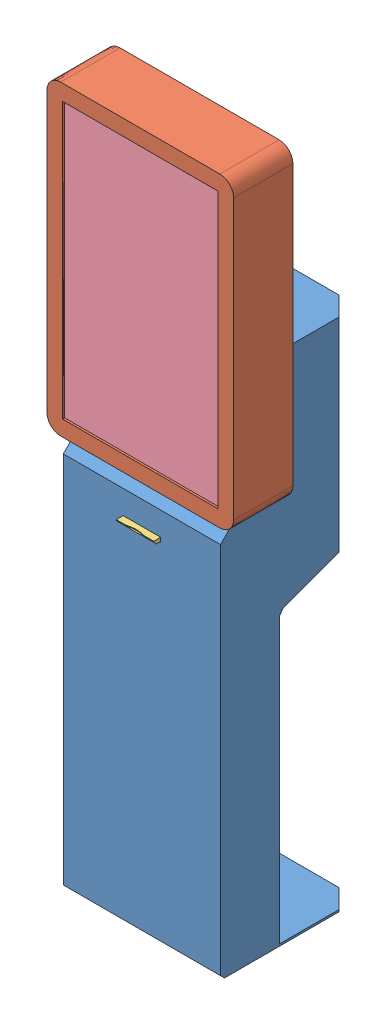
SolidWorks assembly 0NBK, configuration Default. Lengths in mm.
Overall size (475 1780 367.45).
4 component instances, 4 part files, 9 mates.
Components (placement in the parent):
- BodyNBK-1: BodyNBK [Default] at (-208.3287 -13.927 -377.4043) size (400 1310.7 350)
- Screen32-1: Screen32 [Default] at (-205.8287 1026.073 -23.1532) x (-1 0 0) z (0 0 -1) size (475 780 151)
- thermal printer-1: thermal printer [Default] at (-8.3287 825.073 -90.9043) size (132 144.55 271.2)
- TouchScreen32inch-1: TouchScreen32inch [Default] at (-228.4287 1008.3031 -48.7532) x (0 -1 0) z (-1 0 0) size (733 113.4 446.1)
Mates (geometry in assembly coordinates):
- Coincident1: coincident anti-aligned: plane of BodyNBK-1 through (191.6713 986.073 -174.1532) normal (0 0 1); plane of Screen32-1 through (-210.8287 1021.073 -174.1532) normal (0 0 -1)
- Coincident2: coincident anti-aligned: plane of BodyNBK-1 through (191.6713 986.073 -67.4043) normal (0 1 0); plane of Screen32-1 through (194.1713 986.073 -173.1532) normal (0 -1 0)
- Width1: width anti-aligned: plane of Screen32-1 through (229.1713 1731.073 -173.1532) normal (1 0 0); plane of Screen32-1 through (-245.8287 1731.073 -173.1532) normal (-1 0 0); plane of BodyNBK-1 through (-208.3287 -13.927 -377.4043) normal (-1 0 0); plane of BodyNBK-1 through (191.6713 -13.927 -377.4043) normal (1 0 0)
- Coincident5: coincident aligned: plane of thermal printer-1 through (-8.3287 883.373 -28.4043) normal (0 0 1); plane of assembly through (0 0 -28.4043) normal (0 0 1)
- Distance1: distance = 1 mm aligned: plane of TouchScreen32inch-1 through (-228.4287 1008.3031 -24.1532) normal (0 0 1); plane of Screen32-1 through (194.1713 1021.073 -23.1532) normal (0 0 1)
- Parallel3: parallel anti-aligned: plane of Screen32-1 through (-205.8287 1026.073 -173.1532) normal (0 1 0); plane of TouchScreen32inch-1 through (-228.4287 1008.3031 -24.1532) normal (0 -1 0)
- Coincident16: coincident aligned: plane of Screen32-1 through (-205.8287 1026.073 -173.1532) normal (1 0 0); plane of TouchScreen32inch-1 through (-205.8287 1729.8031 -28.4032) normal (1 0 0)
- Width2: width anti-aligned: plane of thermal printer-1 through (-55.9787 886.073 -28.4043) normal (-1 0 0); plane of thermal printer-1 through (39.3213 876.673 -28.4043) normal (1 0 0); plane of BodyNBK-1 through (191.6713 -13.927 -377.4043) normal (1 0 0); plane of BodyNBK-1 through (-208.3287 -13.927 -377.4043) normal (-1 0 0)
- Coincident17: coincident anti-aligned: plane of BodyNBK-1 through (-55.8287 886.073 -136.4043) normal (0 -1 0); plane of thermal printer-1 through (39.3213 886.073 -28.4043) normal (0 1 0)
